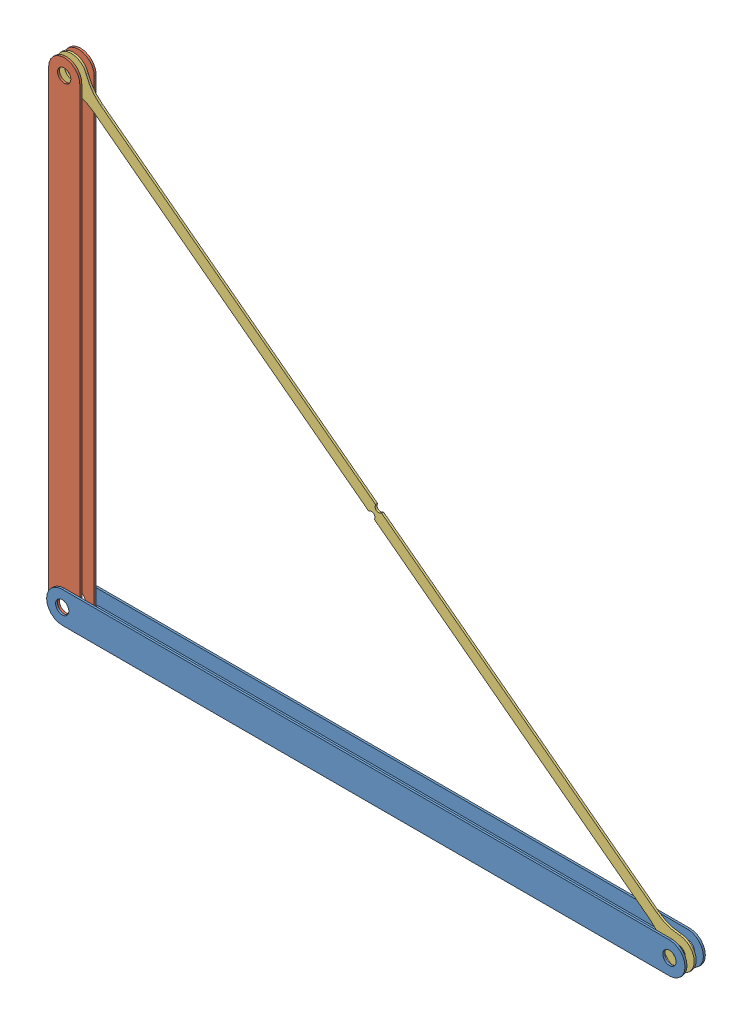
SolidWorks assembly truss, configuration Default. Lengths in mm.
Overall size (396.61 306.62 12.4).
3 component instances, 3 part files, 7 mates.
Components (placement in the parent):
- I_beam_370L-1: I_beam_370L [Default] at (388.9893 243.6952 766.5857) x (-0.000019 -1 0) z (-1 0.000019 0) size (19 12.4 389)
- I_beam_280L-1: I_beam_280L [Default] at (9.5 533.2024 766.5857) x (-1 0 0) z (0 -1 0) size (19 10 299)
- tensionbeam-1: tensionbeam [Default] at (194.4946 383.6989 765.9857) x (-0.797391 0.603463 0) z (0 0 1) size (483 19 1.2)
Mates (geometry in assembly coordinates):
- Coincident6: coincident: line of I_beam_280L-1 through (0 243.7024 771.5857) axis (0 1 0)
- Concentric7: concentric: circle of I_beam_280L-1; circle of tensionbeam-1
- Concentric8: concentric: circle of I_beam_370L-1; circle of tensionbeam-1
- Parallel3: parallel: plane of I_beam_370L-1 through (-0.0107 243.7025 772.7857) normal (0 0 1); plane of tensionbeam-1 through (194.4946 383.6989 767.1857) normal (0 0 1)
- Parallel4: parallel anti-aligned: plane of I_beam_280L-1 through (9.5 234.2024 761.5857) normal (0 0 -1)
- Coincident13: coincident anti-aligned: plane of I_beam_370L-1 through (-0.0107 243.7025 771.5857) normal (0 0 -1); plane of I_beam_280L-1 through (9.5 234.2024 771.5857) normal (0 0 1)
- Distance3: distance = 4.4 mm: plane of tensionbeam-1 through (194.4946 383.6989 767.1857) normal (0 0 1); plane of I_beam_370L-1 through (-0.0107 243.7025 771.5857) normal (0 0 -1)
